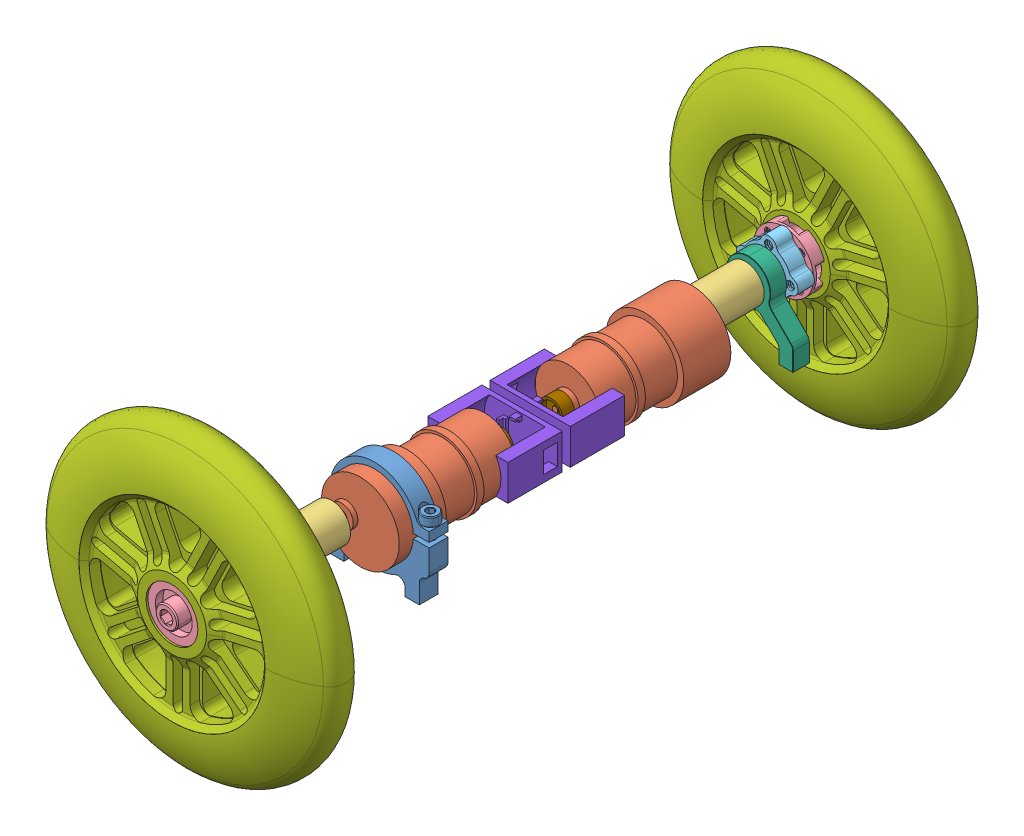
SolidWorks assembly DriveBase, configuration Default. Lengths in mm.
Overall size (124.46 124.46 293.2).
24 component instances, 11 part files, 3 mates.
Components (placement in the parent):
- DriveAssemblyLeft-1: DriveAssemblyLeft [Default] at (-13.1108 55.1108 149.3123) size (124.46 124.46 144.88)
  - 1400-0032-0032 assembly.STEP-1: 1400-0032-0032 assembly.STEP [Default] at (6.581 -3.5947 -1.114) size (42.17 43 8)
  - Motor-2: Motor [Default] at (-2.6241 5.961 7.9343) x (0 0 -1) z (0 1 0) size (70.6 33 33)
  - Coupler-1: Coupler [Default] at (-8.6241 5.961 25.3343) x (0 0 1) z (-0.88407 -0.467355 0) size (22.5 16 16)
  - 595630 assembly.STEP-1: 595630 assembly.STEP [Default] at (-50.3353 -14.4315 51.5475) x (-0.997959 -0.063851 0) z (-0.063851 0.997959 0) size (25.39 31.39 25.39)
  - 545579 assembly.STEP-1: 545579 assembly.STEP [Default] at (19.7418 -41.3992 66.5368) x (0.750814 -0.660514 0) z (0.660514 0.750814 0) size (20.57 9.61 20.57)
  - 1602-0032-0250 assembly.STEP-1: 1602-0032-0250 assembly.STEP [Default] at (-40.6325 25.9608 25.7882) x (-1 0 0) z (0 -1 0) size (38 7 33.35)
  - 3608-0001-0125 assembly.STEP-1: 3608-0001-0125 assembly.STEP [Default] at (-21.1121 15.7426 69.8072) size (124.46 124.46 23.93)
  - Encoder_BracketMount_V2-1: Encoder_BracketMount_V2 [Default] at (-2.6241 5.961 -58.6657) x (0 1 0) z (0 0 1) size (15 34 23)
  - Encoder_MagnetMount_V2-1: Encoder_MagnetMount_V2 [Default] at (-2.6241 5.961 -49.8657) x (-1 0 0) z (0 0 -1) size (10 10 5)
  - 634060-1: 634060 [Default] at (-8.6241 5.961 55.6343) x (0 -1 0) z (1 0 0) size (5.71 25.4 6.34)
  - MotorMount-1: MotorMount [Default] at (-2.6241 5.961 11.1093) size (54 48 23.2)
- DriveAssemblyRight-1: DriveAssemblyRight [Default] at (-18.359 55.1108 24.531) x (-1 0 0) z (0 0 -1) size (124.46 124.46 144.88)
  - 1400-0032-0032 assembly.STEP-1: 1400-0032-0032 assembly.STEP [Default] at (6.581 -3.5947 -1.114) size (42.17 43 8) (hidden)
  - Motor-2: Motor [Default] at (-2.6241 5.961 7.9343) x (0 0 -1) z (0 -1 0) size (70.6 33 33)
  - Coupler-1: Coupler [Default] at (3.3759 5.961 25.3343) x (0 0 1) z (-0.88407 -0.467355 0) size (22.5 16 16)
  - 595630 assembly.STEP-1: 595630 assembly.STEP [Default] at (-38.3353 -14.4315 51.5475) x (-0.997959 -0.063851 0) z (-0.063851 0.997959 0) size (25.39 31.39 25.39)
  - 545579 assembly.STEP-1: 545579 assembly.STEP [Default] at (31.7418 -41.3992 66.5368) x (0.750814 -0.660514 0) z (0.660514 0.750814 0) size (20.57 9.61 20.57)
  - 1602-0032-0250 assembly.STEP-1: 1602-0032-0250 assembly.STEP [Default] at (-28.6325 25.9608 25.7882) x (-1 0 0) z (0 -1 0) size (38 7 33.35)
  - 3608-0001-0125 assembly.STEP-1: 3608-0001-0125 assembly.STEP [Default] at (-9.1121 15.7426 69.8072) size (124.46 124.46 23.93)
  - Encoder_BracketMount_V2-1: Encoder_BracketMount_V2 [Default] at (-2.6241 5.961 -58.6657) x (0 1 0) z (0 0 1) size (15 34 23)
  - Encoder_MagnetMount_V2-1: Encoder_MagnetMount_V2 [Default] at (-2.6241 5.961 -49.8657) x (-1 0 0) z (0 0 -1) size (10 10 5)
  - 634060-1: 634060 [Default] at (3.3759 5.961 55.6343) x (0 -1 0) z (1 0 0) size (5.71 25.4 6.34)
  - MotorMount-1: MotorMount [Default] at (-2.6241 5.961 11.1093) size (54 48 23.2)
Mates (geometry in assembly coordinates):
- Coincident1: coincident aligned: plane of DriveAssemblyLeft-1/1400-0032-0032 assembly.STEP-1 through (-2.7349 37.0718 151.2466) normal (0 -1 0); plane of DriveAssemblyRight-1/1400-0032-0032 assembly.STEP-1 through (-2.7349 37.0718 22.5966) normal (0 -1 0)
- Coincident2: coincident aligned: plane of DriveAssemblyLeft-1/1400-0032-0032 assembly.STEP-1 through (3.2651 37.0718 151.2466) normal (1 0 0); plane of DriveAssemblyRight-1/1400-0032-0032 assembly.STEP-1 through (3.2651 37.0718 22.5966) normal (1 0 0)
- Distance1: distance = 120.65 mm aligned: plane of DriveAssemblyRight-1/1400-0032-0032 assembly.STEP-1 through (-15.7349 61.0718 30.5966) normal (0 0 1); plane of DriveAssemblyLeft-1/1400-0032-0032 assembly.STEP-1 through (-15.7349 61.0718 151.2466) normal (0 0 1)
